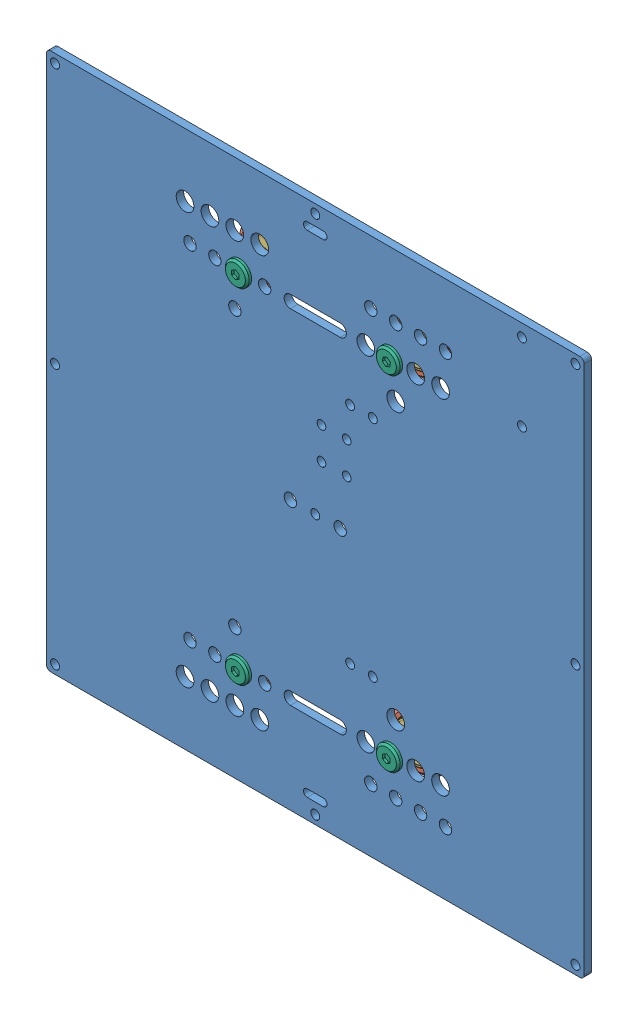
SolidWorks assembly Assem2, configuration Default. Lengths in mm.
Overall size (216 216 27.2).
33 component instances, 7 part files, 7 mates.
Components (placement in the parent):
- V-Slot Universal Build Plate-1: V-Slot Universal Build Plate [Default] at (-53.2124 10.1898 21.1567) size (216 216 3)
- V-Slot Delrin Dual Wheel Assembly-1: V-Slot Delrin Dual Wheel Assembly [Default] at (-87.7089 66.118 18.8913) size (23.89 23.89 27.2)
  - Delrin Dual V-Wheel-1: Delrin Dual V-Wheel [Default] at (4.1766 13.0717 -11.0846) size (23.89 23.89 10.23)
  - Precision Ball Bearing-1: Precision Ball Bearing [Default] at (4.1766 13.0717 -8.0846) x (0 0 -1) z (1 0 0) size (5 16 16)
  - Precision Ball Bearing-2: Precision Ball Bearing [Default] at (4.1766 13.0717 -14.0846) x (0 0 -1) z (1 0 0) size (5 16 16)
  - 5mm Precision Washer-1: 5mm Precision Washer [Default] at (4.1766 13.0717 -11.5846) x (0 0 1) z (-1 0 0) size (1 10 10)
  - .25 Inch Aluminum Spacer-1: .25 Inch Aluminum Spacer [Default] at (4.1766 13.0717 0.7654) x (0 0 -1) z (1 0 0) size (6.35 8 8)
  - 5mm Low Profile Socket Head Screw - Multiple Lengths-1: 5mm Low Profile Socket Head Screw - Multiple Lengths [Default] at (4.1766 13.0717 5.5154) x (0 0 -1) z (1 0 0) size (27.2 9.5 9.5)
  - Nylon Insert Hex Locknut 5mm-1: Nylon Insert Hex Locknut 5mm [Default] at (4.1766 13.0717 -16.5846) x (-0.923728 -0.383049 0) z (0 0 -1) size (7.68 8.82 4.5)
- V-Slot Delrin Dual Wheel Assembly-2: V-Slot Delrin Dual Wheel Assembly [Default] at (-87.7089 -71.882 18.8913) size (23.89 23.89 27.2)
  - Delrin Dual V-Wheel-1: Delrin Dual V-Wheel [Default] at (4.1766 13.0717 -11.0846) size (23.89 23.89 10.23)
  - Precision Ball Bearing-1: Precision Ball Bearing [Default] at (4.1766 13.0717 -8.0846) x (0 0 -1) z (1 0 0) size (5 16 16)
  - Precision Ball Bearing-2: Precision Ball Bearing [Default] at (4.1766 13.0717 -14.0846) x (0 0 -1) z (1 0 0) size (5 16 16)
  - 5mm Precision Washer-1: 5mm Precision Washer [Default] at (4.1766 13.0717 -11.5846) x (0 0 1) z (-1 0 0) size (1 10 10)
  - .25 Inch Aluminum Spacer-1: .25 Inch Aluminum Spacer [Default] at (4.1766 13.0717 0.7654) x (0 0 -1) z (1 0 0) size (6.35 8 8)
  - 5mm Low Profile Socket Head Screw - Multiple Lengths-1: 5mm Low Profile Socket Head Screw - Multiple Lengths [Default] at (4.1766 13.0717 5.5154) x (0 0 -1) z (1 0 0) size (27.2 9.5 9.5)
  - Nylon Insert Hex Locknut 5mm-1: Nylon Insert Hex Locknut 5mm [Default] at (4.1766 13.0717 -16.5846) x (-0.923728 -0.383049 0) z (0 0 -1) size (7.68 8.82 4.5)
- V-Slot Delrin Dual Wheel Assembly-3: V-Slot Delrin Dual Wheel Assembly [Default] at (-15.3542 67.7229 18.8913) x (0.62878 0.777583 0) z (0 0 1) size (23.89 23.89 27.2)
  - Delrin Dual V-Wheel-1: Delrin Dual V-Wheel [Default] at (4.1766 13.0717 -11.0846) size (23.89 23.89 10.23)
  - Precision Ball Bearing-1: Precision Ball Bearing [Default] at (4.1766 13.0717 -8.0846) x (0 0 -1) z (1 0 0) size (5 16 16)
  - Precision Ball Bearing-2: Precision Ball Bearing [Default] at (4.1766 13.0717 -14.0846) x (0 0 -1) z (1 0 0) size (5 16 16)
  - 5mm Precision Washer-1: 5mm Precision Washer [Default] at (4.1766 13.0717 -11.5846) x (0 0 1) z (-1 0 0) size (1 10 10)
  - .25 Inch Aluminum Spacer-1: .25 Inch Aluminum Spacer [Default] at (4.1766 13.0717 0.7654) x (0 0 -1) z (1 0 0) size (6.35 8 8)
  - 5mm Low Profile Socket Head Screw - Multiple Lengths-1: 5mm Low Profile Socket Head Screw - Multiple Lengths [Default] at (4.1766 13.0717 5.5154) x (0 0 -1) z (1 0 0) size (27.2 9.5 9.5)
  - Nylon Insert Hex Locknut 5mm-1: Nylon Insert Hex Locknut 5mm [Default] at (4.1766 13.0717 -16.5846) x (-0.923728 -0.383049 0) z (0 0 -1) size (7.68 8.82 4.5)
- V-Slot Delrin Dual Wheel Assembly-4: V-Slot Delrin Dual Wheel Assembly [Default] at (-27.0689 -71.882 18.8913) size (23.89 23.89 27.2)
  - Delrin Dual V-Wheel-1: Delrin Dual V-Wheel [Default] at (4.1766 13.0717 -11.0846) size (23.89 23.89 10.23)
  - Precision Ball Bearing-1: Precision Ball Bearing [Default] at (4.1766 13.0717 -8.0846) x (0 0 -1) z (1 0 0) size (5 16 16)
  - Precision Ball Bearing-2: Precision Ball Bearing [Default] at (4.1766 13.0717 -14.0846) x (0 0 -1) z (1 0 0) size (5 16 16)
  - 5mm Precision Washer-1: 5mm Precision Washer [Default] at (4.1766 13.0717 -11.5846) x (0 0 1) z (-1 0 0) size (1 10 10)
  - .25 Inch Aluminum Spacer-1: .25 Inch Aluminum Spacer [Default] at (4.1766 13.0717 0.7654) x (0 0 -1) z (1 0 0) size (6.35 8 8)
  - 5mm Low Profile Socket Head Screw - Multiple Lengths-1: 5mm Low Profile Socket Head Screw - Multiple Lengths [Default] at (4.1766 13.0717 5.5154) x (0 0 -1) z (1 0 0) size (27.2 9.5 9.5)
  - Nylon Insert Hex Locknut 5mm-1: Nylon Insert Hex Locknut 5mm [Default] at (4.1766 13.0717 -16.5846) x (-0.923728 -0.383049 0) z (0 0 -1) size (7.68 8.82 4.5)
Mates (geometry in assembly coordinates):
- Coincident1: coincident: plane of V-Slot Universal Build Plate-1 through (-159.4624 -96.0602 22.6567) normal (0 0 1); plane of V-Slot Delrin Dual Wheel Assembly-3/5mm Low Profile Socket Head Screw - Multiple Lengths-1 through (84.7108 40.3829 22.6567) normal (0 0 -1)
- Coincident2: coincident anti-aligned: plane of V-Slot Universal Build Plate-1 through (-159.4624 -96.0602 22.6567) normal (0 0 1); plane of V-Slot Delrin Dual Wheel Assembly-4/5mm Low Profile Socket Head Screw - Multiple Lengths-1 through (-22.8924 -56.3102 22.6567) normal (0 0 -1)
- Coincident3: coincident anti-aligned: plane of V-Slot Universal Build Plate-1 through (-159.4624 -96.0602 22.6567) normal (0 0 1); plane of V-Slot Delrin Dual Wheel Assembly-1/5mm Low Profile Socket Head Screw - Multiple Lengths-1 through (-83.5324 81.6898 22.6567) normal (0 0 -1)
- Coincident4: coincident anti-aligned: plane of V-Slot Universal Build Plate-1 through (-159.4624 -96.0602 22.6567) normal (0 0 1); plane of V-Slot Delrin Dual Wheel Assembly-2/5mm Low Profile Socket Head Screw - Multiple Lengths-1 through (-83.5324 -56.3102 22.6567) normal (0 0 -1)
- Concentric3: concentric anti-aligned: cylinder of V-Slot Universal Build Plate-1 through (-83.5324 -58.8102 22.6567) axis (0 0 -1) radius 2.5; cylinder of V-Slot Delrin Dual Wheel Assembly-2/.25 Inch Aluminum Spacer-1 through (-83.5324 -58.8102 13.3067) axis (0 0 1) radius 4
- Concentric4: concentric anti-aligned: cylinder of V-Slot Universal Build Plate-1 through (-83.5324 79.1898 22.6567) axis (0 0 -1) radius 2.5; cylinder of V-Slot Delrin Dual Wheel Assembly-1/.25 Inch Aluminum Spacer-1 through (-83.5324 79.1898 13.3067) axis (0 0 1) radius 4
- Concentric5: concentric anti-aligned: cylinder of V-Slot Universal Build Plate-1 through (-22.8924 79.1898 22.6567) axis (0 0 -1) radius 3.57; cylinder of V-Slot Delrin Dual Wheel Assembly-3/.25 Inch Aluminum Spacer-1 through (-22.8924 79.1898 13.3067) axis (0 0 1) radius 4
